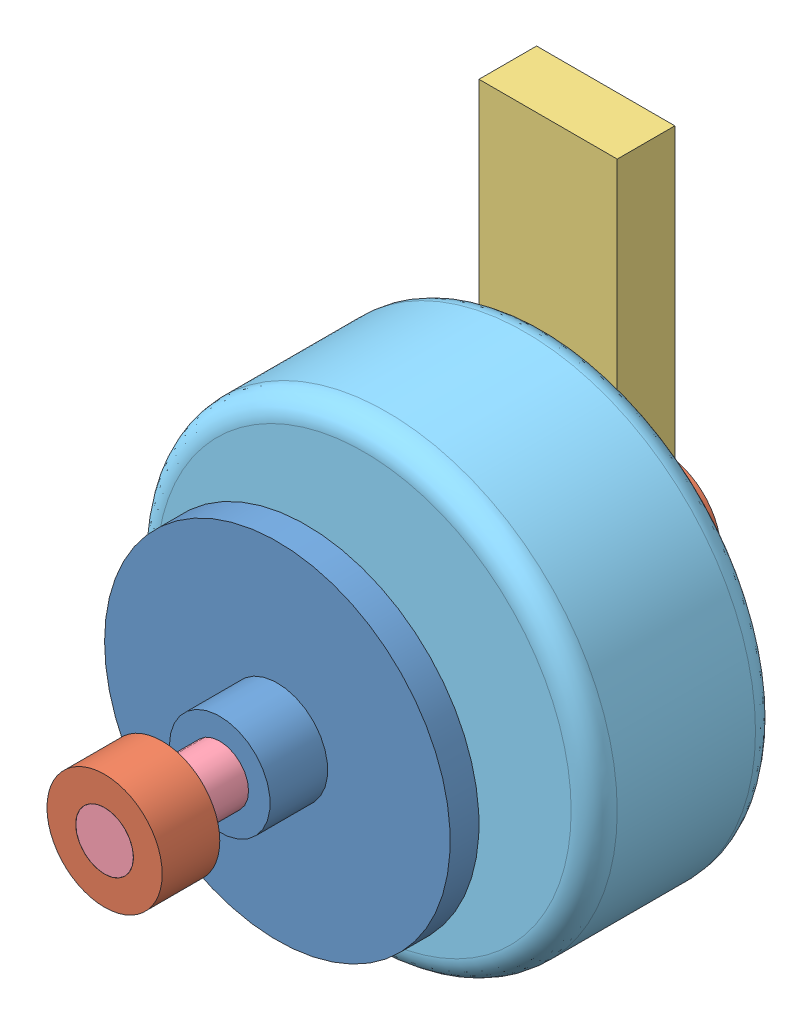
SolidWorks assembly Front Wheel Assembly, configuration Default. Lengths in mm.
Overall size (50.8 69.85 61.59).
6 component instances, 5 part files, 10 mates.
Components (placement in the parent):
- 72-Gear-1: 72-Gear [Default] at (6.763 17.5096 30.0306) size (38.1 38.1 9.53)
- Axel Washer-1: Axel Washer [Default] at (6.763 17.5096 45.9056) size (12.7 12.7 6.35)
- Front Wheel Support-1: Front Wheel Support [Default] at (6.763 17.5096 -2.9894) size (15.24 52.07 6.35)
- Front Wheels Axel-1: Front Wheels Axel [Default] at (6.763 17.5096 -9.3394) size (6.35 6.35 61.59)
- Wheel-1: Wheel [Default] at (6.763 17.5096 3.3606) size (50.8 50.8 20.32)
- Axel Washer-2: Axel Washer [Default] at (6.763 17.5096 -9.3394) size (12.7 12.7 6.35)
Mates (geometry in assembly coordinates):
- Coincident1: coincident aligned: plane of Axel Washer-1 through (6.763 17.5096 52.2556) normal (0 0 1); plane of Front Wheels Axel-1 through (6.763 17.5096 52.2556) normal (0 0 1)
- Concentric1: concentric aligned: cylinder of Axel Washer-1 through (6.763 17.5096 52.2556) axis (0 0 -1) radius 3.175; cylinder of Front Wheels Axel-1 through (6.763 17.5096 52.2556) axis (0 0 -1) radius 3.175
- Coincident2: coincident aligned: plane of Front Wheels Axel-1 through (6.763 17.5096 -9.3394) normal (0 0 -1); plane of Axel Washer-2 through (6.763 17.5096 -9.3394) normal (0 0 -1)
- Concentric3: concentric aligned: cylinder of Front Wheels Axel-1 through (6.763 17.5096 52.2556) axis (0 0 -1) radius 3.175; cylinder of Axel Washer-2 through (6.763 17.5096 -2.9894) axis (0 0 -1) radius 3.175
- Coincident3: coincident anti-aligned: plane of Front Wheel Support-1 through (6.763 17.5096 -2.9894) normal (0 0 -1); plane of Axel Washer-2 through (6.763 17.5096 -2.9894) normal (0 0 1)
- Concentric4: concentric aligned: cylinder of Front Wheel Support-1 through (6.763 17.5096 3.3606) axis (0 0 -1) radius 3.175; cylinder of Front Wheels Axel-1 through (6.763 17.5096 52.2556) axis (0 0 -1) radius 3.175
- Coincident4: coincident anti-aligned: plane of Front Wheel Support-1 through (6.763 17.5096 3.3606) normal (0 0 1); plane of Wheel-1 through (6.763 17.5096 3.3606) normal (0 0 -1)
- Concentric5: concentric aligned: cylinder of Front Wheels Axel-1 through (6.763 17.5096 52.2556) axis (0 0 -1) radius 3.175; cylinder of Wheel-1 through (6.763 17.5096 23.6806) axis (0 0 -1) radius 3.175
- Distance1: distance = 12.7 mm aligned: plane of 72-Gear-1 through (6.763 17.5096 39.5556) normal (0 0 1); plane of Axel Washer-1 through (6.763 17.5096 52.2556) normal (0 0 1)
- Concentric6: concentric aligned: cylinder of 72-Gear-1 through (6.763 17.5096 39.5556) axis (0 0 -1) radius 3.175; cylinder of Front Wheels Axel-1 through (6.763 17.5096 52.2556) axis (0 0 -1) radius 3.175
